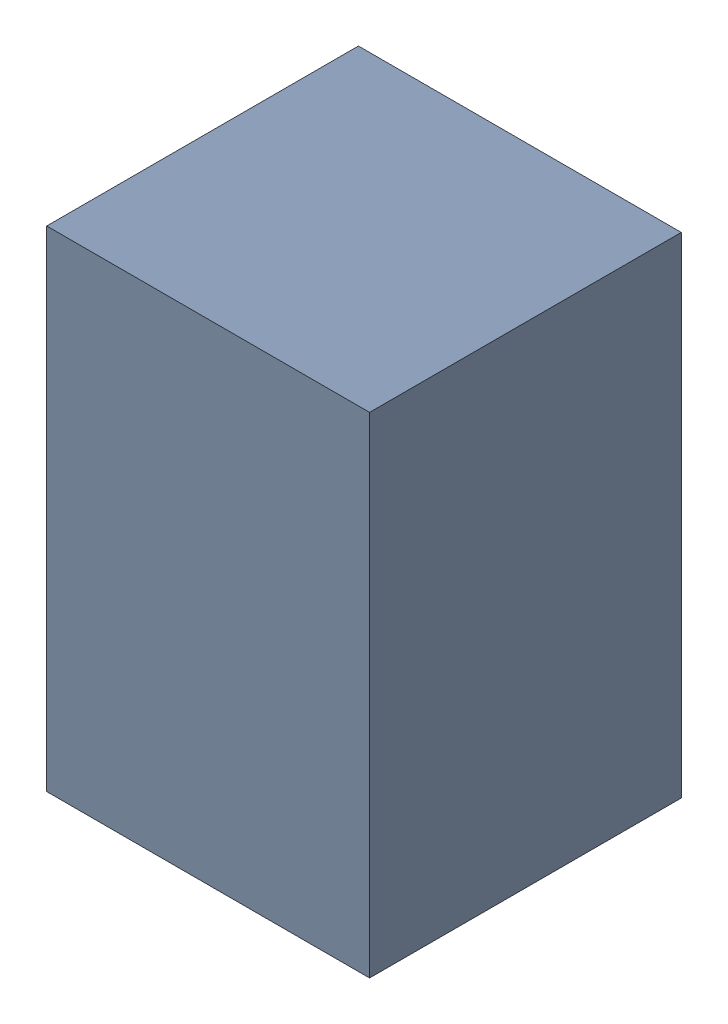
SolidWorks assembly D3-1, configuration Default. Lengths in mm.
Overall size (1.45 2.2 1.4).
2 component instances, 1 part files, 0 mates.
Components (placement in the parent):
- 959209888-1-1: 959209888-1 [Default] at (108.585 90.769 0) size (1.45 2.2 1.4)
  - Extruded-60-1: Extruded-60 [Default] at origin size (1.45 2.2 1.4)
